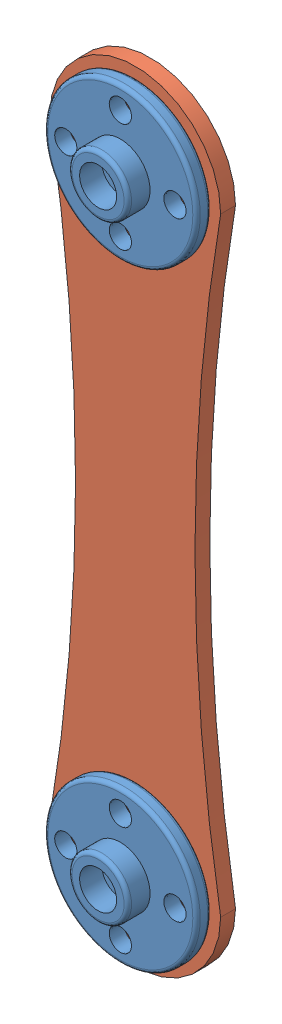
SolidWorks assembly 大腿与舵盘装配图, configuration 默认. Lengths in mm.
Overall size (23 105 7).
3 component instances, 2 part files, 6 mates.
Components (placement in the parent):
- 舵盘-3: 舵盘 [默认] at (-98.0199 84.1053 59.4893) size (20.5 20.5 5)
- 舵盘-4: 舵盘 [默认] at (-98.0199 166.1053 59.4893) size (20.5 20.5 5)
- 大腿-3: 大腿 [默认] at (-151.4506 154.4869 57.4893) size (23 105 2)
Mates (geometry in assembly coordinates):
- 同心4: concentric anti-aligned: circle of 舵盘-3; circle of 大腿-3
- 同心5: concentric anti-aligned: circle of 舵盘-3; circle of 大腿-3
- 同心6: concentric aligned: circle of 舵盘-4; circle of 大腿-3
- 同心7: concentric anti-aligned: circle of 舵盘-4; circle of 大腿-3
- 重合2: coincident anti-aligned: plane of 舵盘-4 through (-98.0199 166.1053 59.4893) normal (0 0 -1); plane of 大腿-3 through (-151.4506 154.4869 59.4893) normal (0 0 1)
- 重合3: coincident anti-aligned: plane of 舵盘-3 through (-98.0199 84.1053 59.4893) normal (0 0 -1); plane of 大腿-3 through (-151.4506 154.4869 59.4893) normal (0 0 1)
